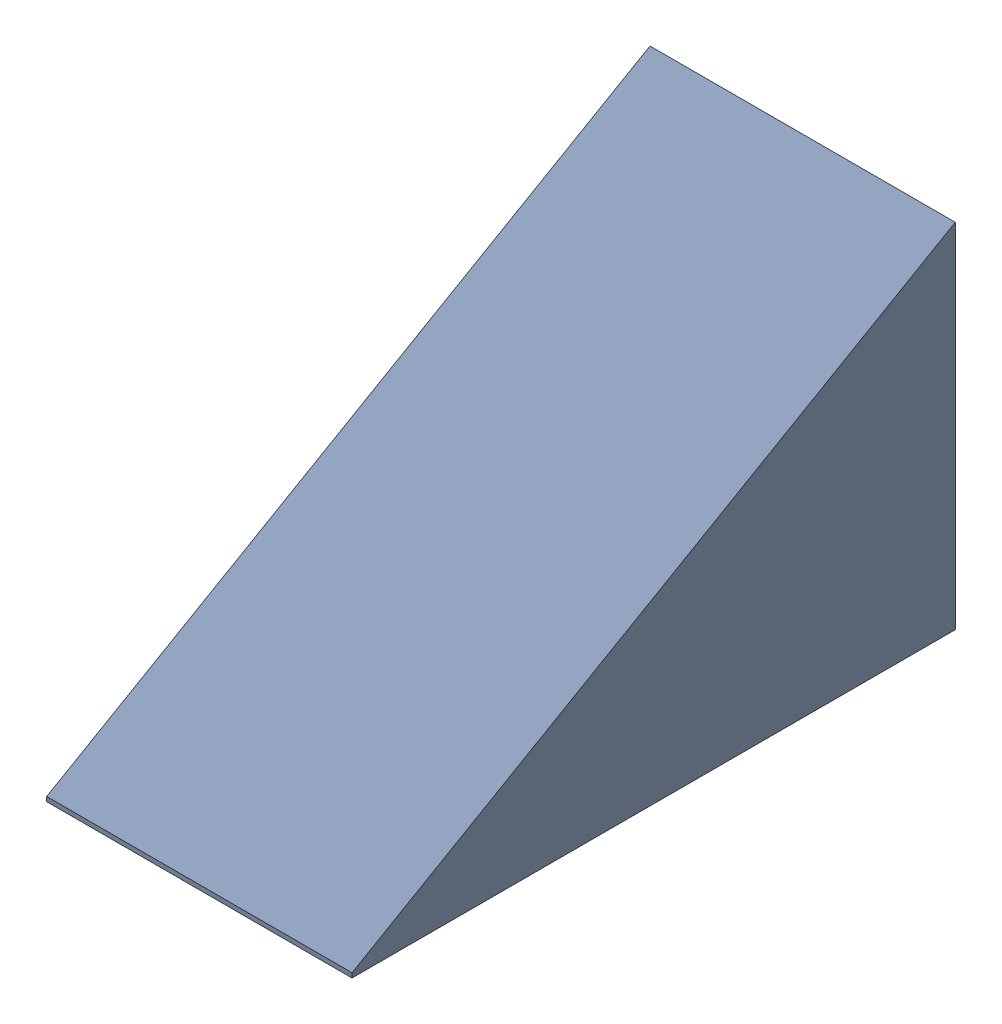
SolidWorks assembly Displacer, configuration Default. Lengths in mm.
Overall size (85.72 99.06 169.38).
2 component instances, 2 part files, 3 mates.
Components (placement in the parent):
- channel-1: channel [8-32 insert] at origin size (85.72 99.06 169.38)
- 93365A140_Tapered Heat-Set Inserts for Plastic-1: 93365A140_Tapered Heat-Set Inserts for Plastic [93365A140] at (0 0 2.3495) x (-0.923728 -0.383049 0) z (0 0 -1) size (6.37 6.37 4.7)
Mates (geometry in assembly coordinates):
- Coincident1: coincident aligned: plane of channel-1 through (811.6866 285.2633 -356.7187) normal (0 0 -1); plane of 93365A140_Tapered Heat-Set Inserts for Plastic-1 through (860.0198 245.2867 -356.7187) normal (0 0 -1)
- Concentric2: concentric anti-aligned: cone of channel-1 through (861.2166 242.4008 -356.7187) axis (0 0 1); cylinder of 93365A140_Tapered Heat-Set Inserts for Plastic-1 through (861.2166 242.4008 -356.7187) axis (0 0 -1) radius 3.175
- Coincident2: coordinate: point of channel-1
